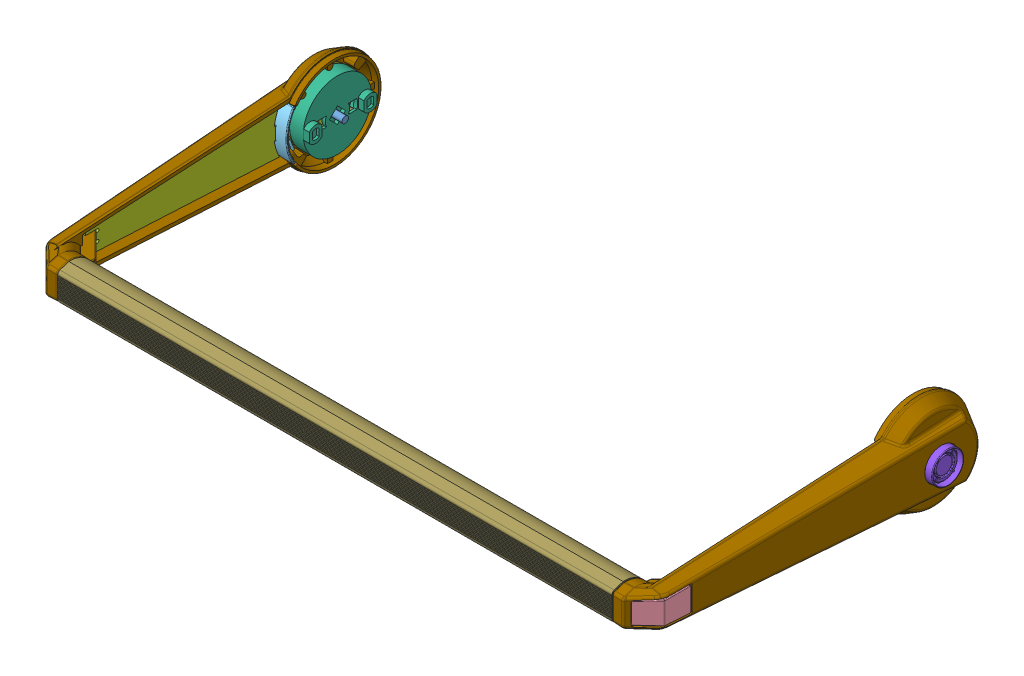
SolidWorks assembly 24576-072-o, configuration По умолчанию. Lengths in mm.
Overall size (403.98 60 209.99).
25 component instances, 12 part files, 0 mates.
Components (placement in the parent):
- GRIFFSEITENTEIL-180-1: GRIFFSEITENTEIL-180 [По умолчанию] at (178.14 0 0) size (39.1 60 209.99)
  - LI--KO-SHR-M4x20-S-1: LI--KO-SHR-M4x20-S [По умолчанию] at (15.1 0 0) x (0 0 -1) z (1 0 0) size (8 8 23.08)
  - SCHEIBE-A43-SN27---1: SCHEIBE-A43-SN27-- [По умолчанию] at (15.1 0 0) x (0 0 -1) z (1 0 0) size (12 12 1)
  - STERNSCHEIBE-1: STERNSCHEIBE [По умолчанию] at origin size (2.5 38 38)
  - KAPPE-1: KAPPE [По умолчанию] at origin size (14.76 15.32 26.63)
  - ABDECKUNG-1: ABDECKUNG [По умолчанию] at origin size (14.07 31.26 14.09)
  - LAGER-1: LAGER [По умолчанию] at origin size (17.6 42.5 42.5)
  - SICHERHEITSLASCHE-180-1: SICHERHEITSLASCHE-180 [По умолчанию] at origin size (17.2 42 195.5)
  - KNOPF-1: KNOPF [По умолчанию] at origin size (19.32 19.8 19.8)
  - GRIFFSEITENTEIL-180-1: GRIFFSEITENTEIL-180 [По умолчанию] at origin size (29.21 60 209.99)
  - ZYL-KO-SHR-M5x16-S-1: ZYL-KO-SHR-M5x16-S [По умолчанию] at (0.75 0 169.25) x (0 0 -1) z (1 0 0) size (8.5 8.5 21)
  - FED-RING-DIN127-B5-1: FED-RING-DIN127-B5 [По умолчанию] at (0.77 0 169.25) x (0 0 -1) z (1 0 0) size (9.2 9.2 1.2)
- GRIFFSEITENTEIL-180-2: GRIFFSEITENTEIL-180 [По умолчанию] at (-178.14 0 0) x (-1 0 0) z (0 0 1) size (39.1 60 209.99)
  - LI--KO-SHR-M4x20-S-1: LI--KO-SHR-M4x20-S [По умолчанию] at (15.1 0 0) x (0 0 -1) z (1 0 0) size (8 8 23.08)
  - SCHEIBE-A43-SN27---1: SCHEIBE-A43-SN27-- [По умолчанию] at (15.1 0 0) x (0 0 -1) z (1 0 0) size (12 12 1)
  - STERNSCHEIBE-1: STERNSCHEIBE [По умолчанию] at origin size (2.5 38 38)
  - KAPPE-1: KAPPE [По умолчанию] at origin size (14.76 15.32 26.63)
  - ABDECKUNG-1: ABDECKUNG [По умолчанию] at origin size (14.07 31.26 14.09)
  - LAGER-1: LAGER [По умолчанию] at origin size (17.6 42.5 42.5)
  - SICHERHEITSLASCHE-180-1: SICHERHEITSLASCHE-180 [По умолчанию] at origin size (17.2 42 195.5)
  - KNOPF-1: KNOPF [По умолчанию] at origin size (19.32 19.8 19.8)
  - GRIFFSEITENTEIL-180-1: GRIFFSEITENTEIL-180 [По умолчанию] at origin size (29.21 60 209.99)
  - ZYL-KO-SHR-M5x16-S-1: ZYL-KO-SHR-M5x16-S [По умолчанию] at (0.75 0 169.25) x (0 0 -1) z (1 0 0) size (8.5 8.5 21)
  - FED-RING-DIN127-B5-1: FED-RING-DIN127-B5 [По умолчанию] at (0.77 0 169.25) x (0 0 -1) z (1 0 0) size (9.2 9.2 1.2)
- GR-STANGE-63TE-----1: GR-STANGE-63TE---- [По умолчанию] at origin size (344.98 20.84 21.8)
